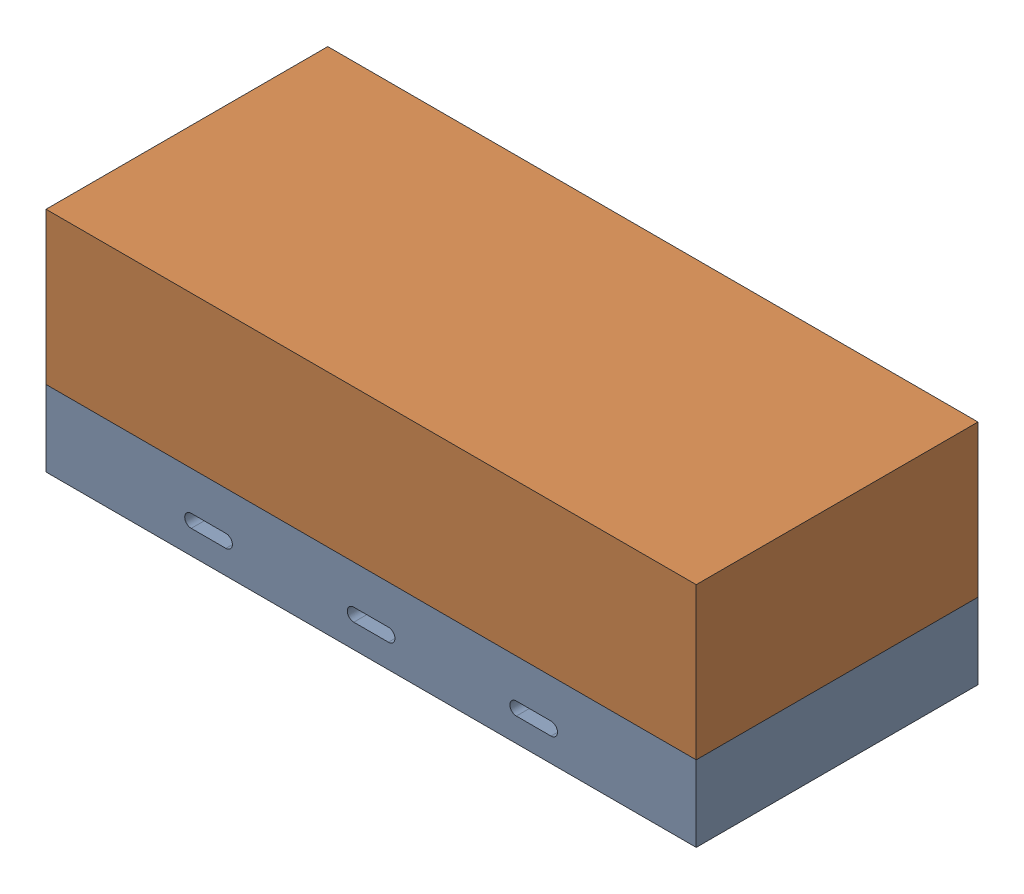
SolidWorks assembly Full Housing 2, configuration Default. Lengths in mm.
Overall size (150 52.5 65).
2 component instances, 2 part files, 6 mates.
Components (placement in the parent):
- Housing Base 2-1: Housing Base 2 [Default] at origin size (150 22.5 65)
- Housing Top 2-1: Housing Top 2 [Default] at (0 17.5 0) size (150 35 65)
Mates (geometry in assembly coordinates):
- Coincident2: coincident: point of Housing Base 2-1
- Coincident3: coincident aligned: plane of Housing Base 2-1 through (0 0 0) normal (0 0 1)
- Coincident4: coincident anti-aligned: plane of Housing Base 2-1 through (0.2347 17.4984 0) normal (0.013411 0.99991 0); plane of Housing Top 2-1 through (0.2347 17.4984 0) normal (-0.013411 -0.99991 0)
- Coincident5: coincident aligned: plane of Housing Base 2-1 through (0 0 0) normal (0 0 1); plane of Housing Top 2-1 through (0.2347 17.4984 0) normal (0 0 1)
- Coincident6: coincident aligned: plane of Housing Base 2-1 through (0 0 0) normal (0.99991 -0.013411 0); plane of Housing Top 2-1 through (0.2347 17.4984 0) normal (0.99991 -0.013411 0)
- Coincident7: coincident aligned: line of Housing Base 2-1 through (-35.75 0 0) axis (0 0.013411 0.99991)
